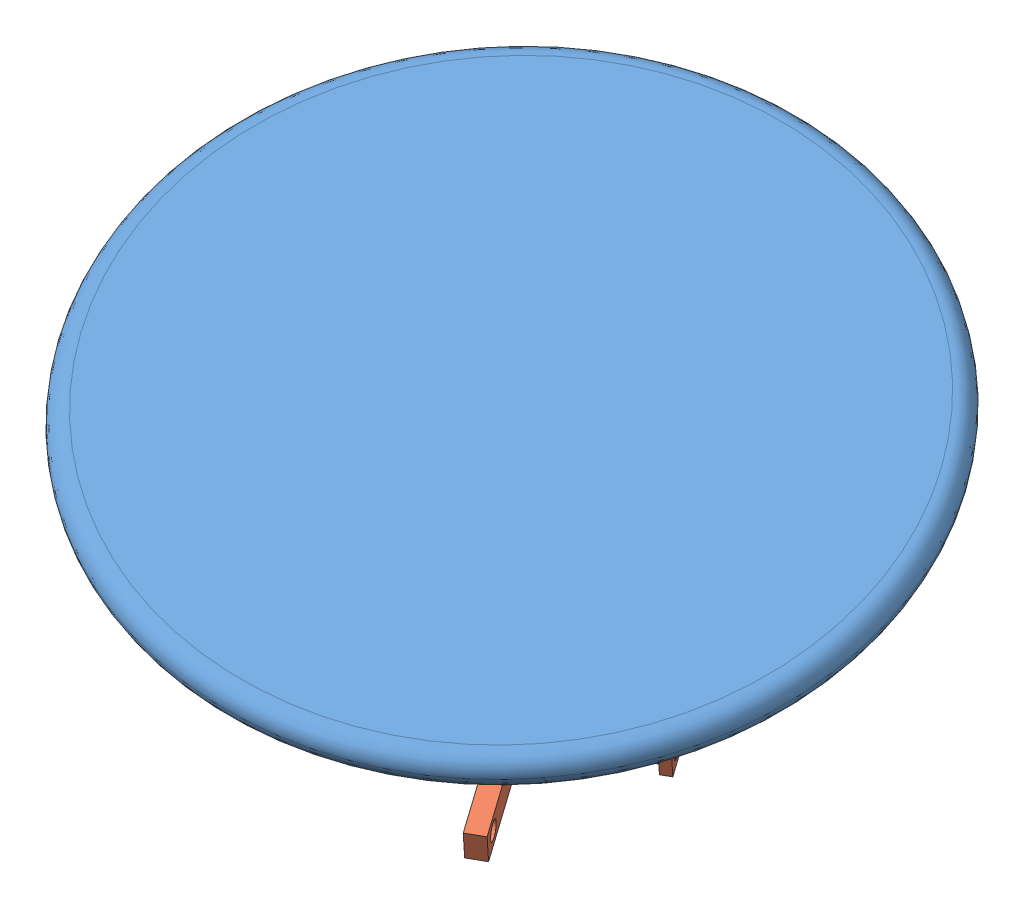
SolidWorks assembly lefttURNwHEEL_1, configuration Default. Lengths in mm.
Overall size (787.04 358.81 796.32).
2 component instances, 2 part files, 0 mates.
Components (placement in the parent):
- pizza wheel_1-1: pizza wheel_1 [Default] at (-55.5421 176.9459 -250.9325) x (0.849801 -0.028004 -0.526359) z (-0.168606 -0.960565 -0.221106) size (558.8 558.8 196.32)
- steeringBracket_1-1: steeringBracket_1 [Default] at (31.3891 7.1803 -128.9838) x (-0.849801 0.028004 0.526359) z (0.49941 -0.276643 0.82101) size (93.42 20.57 203.2)
